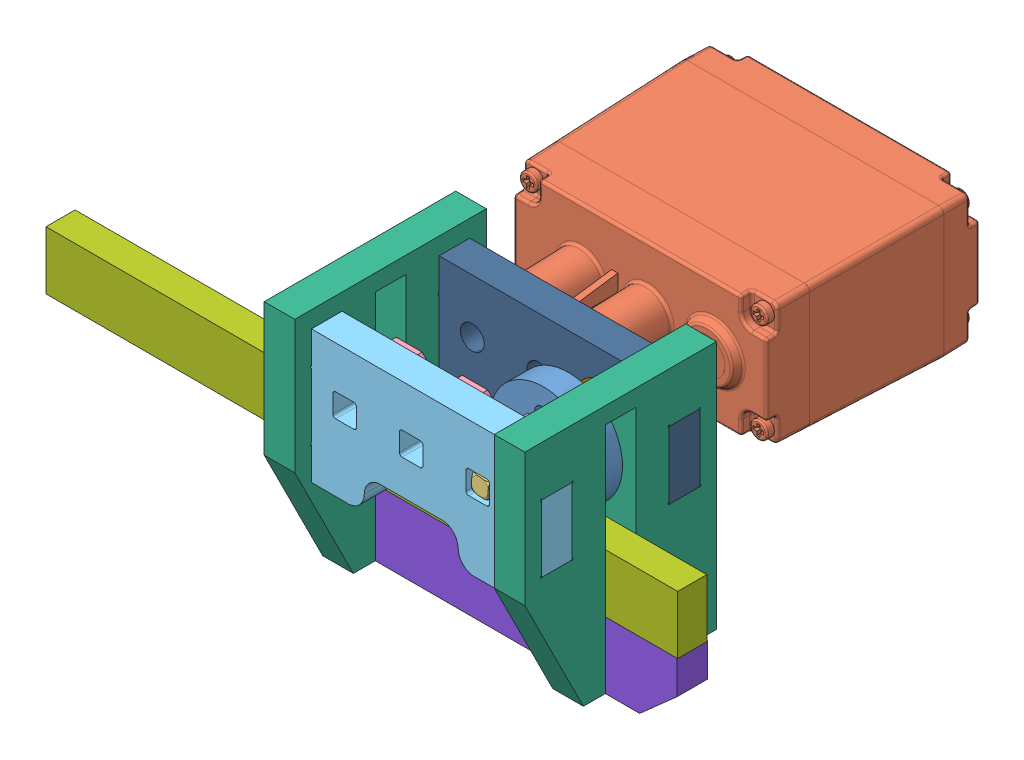
SolidWorks assembly CYLINDER-A-011, configuration Default. Lengths in mm.
Overall size (120.65 47.63 88.41).
11 component instances, 10 part files, 22 mates.
Components (placement in the parent):
- CYLINDER-P-048-1: CYLINDER-P-048 [Default] at (19.4806 -23.7965 1.1188) x (0.998395 0.056625 0) z (0 0 1) size (20.64 20.64 4.76)
- 276-2177-1: 276-2177 [Default] at (-6.2194 -23.8964 -59.7585) x (1 0 0) z (0 1 0) size (56.4 55.81 25)
- 276-2011-1: 276-2011 [Default] at (19.4531 -23.9196 -7.3585) x (0.996289 -0.086075 0) z (0 0 1) size (4.18 4.18 51.01)
- 276-1209-1: 276-1209 [Default] at (-19.6354 -11.0965 -76.3507) x (0 0 1) z (0 1 0) size (7.04 35.56 10.16)
- CYLINDER-P-052-1: CYLINDER-P-052 [Default] at (25.8306 -38.8777 12.6255) size (49.78 25.45 5.84)
- CYLINDER-P-053-1: CYLINDER-P-053 [Default] at (25.8306 -32.5277 12.6255) x (0 0 -1) z (1 0 0) size (36.58 47.62 5.84)
- CYLINDER-P-049-2: CYLINDER-P-049 [Default] at (45.489 -45.2277 0.7192) size (120.65 11.11 5.56)
- CYLINDER-P-053-3: CYLINDER-P-053 [Default] at (-18.1114 -32.5277 12.6255) x (0 0 -1) z (1 0 0) size (36.58 47.62 5.84)
- CYLINDER-P-054-1: CYLINDER-P-054 [Default] at (-5.1054 -57.9277 0.4335) size (63.5 12.7 5.84)
- 276-2010-1: 276-2010 [Default] at (19.4806 -23.7965 -2.2587) x (0.067988 -0.997686 0) z (0 0 1) size (11 11.03 6.6)
- CYLINDER-P-055-1: CYLINDER-P-055 [Default] at (25.8306 -38.9777 -11.7585) size (49.78 25.45 5.84)
Mates (geometry in assembly coordinates):
- Coincident4: coincident anti-aligned: plane of 276-1209-1 through (24.5643 -28.8802 12.6255) normal (0 0 1); plane of CYLINDER-P-052-1 through (-5.3581 -35.7527 12.6255) normal (0 0 -1)
- Coincident9: coincident: line of 276-1209-1 through (18.466 -21.5598 13.3113) axis (-1 0 0); plane of CYLINDER-P-052-1 through (21.2092 -21.5598 18.4675) normal (0 -1 0)
- Coincident10: coincident: line of 276-1209-1 through (21.7172 -22.782 13.3113) axis (0 1 0); plane of CYLINDER-P-052-1 through (21.7172 -25.525 18.4675) normal (-1 0 0)
- Concentric4: concentric anti-aligned: cylinder of CYLINDER-P-048-1 through (19.4806 -23.7965 5.8813) axis (0 0 -1) radius 3.175; cylinder of 276-1209-1 through (19.4806 -23.7965 6.2755) axis (0 0 1) radius 2.1209
- Coincident11: coincident anti-aligned: plane of CYLINDER-P-052-1 through (-5.3581 -35.7527 18.4675) normal (0 0 1); plane of CYLINDER-P-053-1 through (31.6726 -32.5277 18.4675) normal (0 0 -1)
- Distance1: distance = 0.1 mm anti-aligned: plane of CYLINDER-P-053-1 through (31.6726 -32.5277 12.6255) normal (0 1 0); plane of CYLINDER-P-052-1 through (25.8306 -32.6277 18.4675) normal (0 -1 0)
- Coincident14: coincident anti-aligned: plane of CYLINDER-P-052-1 through (25.8306 -19.7277 18.4675) normal (1 0 0); plane of CYLINDER-P-053-1 through (25.8306 -32.5277 12.6255) normal (-1 0 0)
- Coincident18: coincident anti-aligned: plane of CYLINDER-P-053-1 through (31.6726 -45.2277 6.2755) normal (0 0 -1); plane of CYLINDER-P-049-2 through (45.489 -45.2277 6.2755) normal (0 0 1)
- Coincident19: coincident aligned: plane of CYLINDER-P-053-3 through (-18.1114 -32.5277 12.6255) normal (-1 0 0); plane of CYLINDER-P-054-1 through (-18.1114 -51.5777 6.2755) normal (-1 0 0)
- Coincident20: coincident anti-aligned: plane of CYLINDER-P-053-3 through (-12.2694 -51.5777 6.2755) normal (0 1 0); plane of CYLINDER-P-054-1 through (-18.1114 -51.5777 6.2755) normal (0 -1 0)
- Coincident21: coincident anti-aligned: plane of CYLINDER-P-053-3 through (-12.2694 -32.5277 0.4335) normal (0 0 1); plane of CYLINDER-P-054-1 through (-5.1054 -57.9277 0.4335) normal (0 0 -1)
- Coincident22: coincident anti-aligned: plane of CYLINDER-P-052-1 through (-12.2694 -19.7277 18.4675) normal (-1 0 0); plane of CYLINDER-P-053-3 through (-12.2694 -32.5277 12.6255) normal (1 0 0)
- Coincident25: coincident anti-aligned: plane of CYLINDER-P-049-2 through (45.489 -45.2277 6.2755) normal (0 -1 0); plane of CYLINDER-P-054-1 through (-18.1114 -45.2277 6.2755) normal (0 1 0)
- Coincident26: coincident anti-aligned: plane of CYLINDER-P-053-1 through (25.8306 -32.5277 12.6255) normal (-1 0 0); plane of CYLINDER-P-055-1 through (25.8306 -19.8277 -5.9165) normal (1 0 0)
- Coincident27: coincident anti-aligned: plane of CYLINDER-P-053-1 through (31.6726 -19.8277 -5.9165) normal (0 -1 0); plane of CYLINDER-P-055-1 through (25.8306 -19.8277 -5.9165) normal (0 1 0)
- Coincident28: coincident anti-aligned: plane of CYLINDER-P-053-1 through (31.6726 -19.8277 -11.7585) normal (0 0 1); plane of CYLINDER-P-055-1 through (-5.3581 -35.8527 -11.7585) normal (0 0 -1)
- Concentric8: concentric aligned: circle of 276-2177-1; cylinder of CYLINDER-P-055-1 through (-5.9194 -23.8964 -5.9165) axis (0 0 -1) radius 2.286
- Concentric9: concentric aligned: circle of 276-2177-1; cylinder of CYLINDER-P-055-1 through (6.7806 -23.8964 -5.9165) axis (0 0 -1) radius 2.286
- Coincident30: coincident anti-aligned: plane of 276-2177-1 through (-6.2194 -23.8964 -11.7585) normal (0 0 1); plane of CYLINDER-P-055-1 through (-5.3581 -35.8527 -11.7585) normal (0 0 -1)
- Coincident31: coincident anti-aligned: plane of 276-2177-1 through (20.9487 -25.6422 -32.7585) normal (0.086075 0.996289 0); plane of 276-2011-1 through (17.7349 -25.3645 18.0415) normal (-0.086075 -0.996289 0)
- Coincident32: coincident anti-aligned: plane of 276-2177-1 through (18.0125 -22.1507 -32.7585) normal (0.996289 -0.086075 0); plane of 276-2011-1 through (17.7349 -25.3645 18.0415) normal (-0.996289 0.086075 0)
- Coincident33: coincident anti-aligned: plane of 276-2177-1 through (17.7349 -25.3645 -32.7585) normal (0 0 1); plane of 276-2011-1 through (18.0082 -22.2013 -32.7585) normal (0 0 -1)
